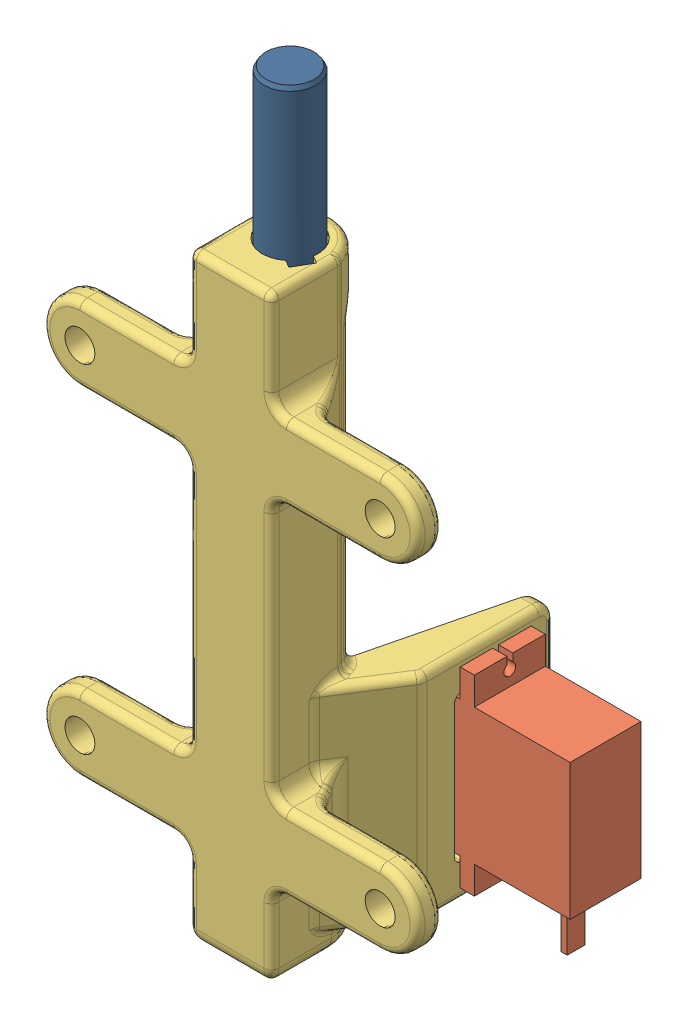
SolidWorks assembly PenHolder, configuration Default. Lengths in mm.
Overall size (64.55 127.8 48.11).
12 component instances, 11 part files, 16 mates.
Components (placement in the parent):
- Servo Lever-1: Servo Lever [Default] at (-0.5 -33.948 -30.734) x (0 -0.984808 -0.173648) z (0 -0.173648 0.984808) size (7.3 5 34)
- SG90 Servo-1: SG90 Servo [Default] at (9.8 -28.448 -30.734) x (0 1 0) z (0 0 1) size (37.7 30.3 12)
- PenHolder-1: PenHolder [Default] at origin size (63.5 101.91 40.64)
- Assembly Ink Cartridge Pilot G2-1: Assembly Ink Cartridge Pilot G2 [Default] at (-23.3837 87.5006 -54.1169) x (1 0 0) z (0 -1 0) size (8.33 8.33 120.93)
  - Ink Container Tube-2: Ink Container Tube [Default] at (23.3837 43.9569 29.8776) x (-1 0 0) z (0 1 0) size (6.2 88 6)
  - Ink Container Back Plug-1: Ink Container Back Plug [Default] at (23.3837 43.9569 29.8776) x (1 0 0) z (0 1 0) size (6 4.9 6)
  - Pen Tip Holder-1: Pen Tip Holder [Default] at (23.3837 43.9569 117.8776) x (0.558829 -0.829283 0) z (0.829283 0.558829 0) size (6 18.11 6)
  - Pen Tip-1: Pen Tip [Default] at (23.3837 43.9569 135.6644) x (0.943336 0.33184 0) z (-0.33184 0.943336 0) size (2.59 15.69 2.63)
  - Roller Ball-2: Roller Ball [Default] at (23.3837 43.9569 138.8644) x (0.307657 -0.299861 -0.903012) z (0.951494 0.099481 0.29114) size (0.5 0.5 0.5)
  - Spring-3: Spring [Write] at (23.3837 43.9569 20.2276) x (1 0 0) z (0 -1 0) size (7.26 11.16 7.26)
- Spring Cap-1: Spring Cap [Default] at (0 19.5395 -10.16) x (0.422618 0 0.906308) z (-0.906308 0 0.422618) size (8.89 56.52 10.92)
- Pen Lifter-1: Pen Lifter [Default] at (0 -42.799 -10.16) x (-1 0 0) z (0 0 -1) size (8.89 15.4 11.43)
Mates (geometry in assembly coordinates):
- Concentric1: concentric anti-aligned: cylinder of Servo Lever-1 through (4.5 -33.948 -30.734) axis (-1 0 0) radius 0.75; cylinder of SG90 Servo-1 through (5.5 -33.948 -30.734) axis (1 0 0) radius 6
- Coincident2: coordinate: point of PenHolder-1
- Concentric4: concentric anti-aligned: cylinder of PenHolder-1 through (0 -47.625 -10.16) axis (0 -1 0) radius 1.397; cylinder of Assembly Ink Cartridge Pilot G2-1/Ink Container Tube-2 through (0 -30.377 -10.16) axis (0 1 0) radius 3
- Coincident7: coincident anti-aligned: plane of Servo Lever-1 through (2.5 -33.948 -30.734) normal (1 0 0); plane of SG90 Servo-1 through (2.5 -28.448 -30.734) normal (-1 0 0)
- Parallel2: parallel aligned: plane of Assembly Ink Cartridge Pilot G2-1 through (-23.3837 87.5006 -54.1169) normal (0 0 1)
- Concentric5: concentric anti-aligned: cylinder of PenHolder-1 through (0 50.8 -10.16) axis (0 -1 0) radius 6.985; cylinder of Spring Cap-1 through (0 73.5145 -10.16) axis (0 1 0) radius 4.445
- Angle1: planar angle = 2.007129 rad anti-aligned: plane of Spring Cap-1 through (0 19.5395 -10.16) normal (-0.906308 0 0.422618)
- Concentric7: concentric anti-aligned: cylinder of PenHolder-1 through (0 50.8 -10.16) axis (0 -1 0) radius 4.699; cylinder of Pen Lifter-1 through (0 -31.877 -10.16) axis (0 1 0) radius 4.445
- Parallel5: parallel anti-aligned: plane of Pen Lifter-1 through (0 -42.799 -10.16) normal (0 0 -1)
- Symmetric2: symmetric aligned: plane of Servo Lever-1 through (-0.5 -31.3867 -45.2599) normal (-1 0 0); plane of Pen Lifter-1 through (0.5 -31.3867 -45.2599) normal (1 0 0); plane of Servo Lever-1 through (0 -42.799 -10.16) normal (-1 0 0)
- LimitAngle1: limit planar angle = 0.174533 rad aligned: plane of Servo Lever-1 through (-0.5 -33.948 -30.734) normal (0 -0.173648 0.984808); plane of SG90 Servo-1 through (9.8 -28.448 -30.734) normal (0 0 1)
- LimitDistance1: limit distance = 4.826 mm anti-aligned: plane of PenHolder-1 through (0 -47.625 -10.16) normal (0 1 0); plane of Pen Lifter-1 through (-4.445 -42.799 -10.16) normal (0 -1 0)
- Coincident14: coincident anti-aligned: plane of Assembly Ink Cartridge Pilot G2-1/Pen Tip Holder-1 through (0 -31.877 -10.16) normal (0 -1 0); plane of Pen Lifter-1 through (-2.3546 -31.877 -10.16) normal (0 1 0)
- Parallel6: parallel anti-aligned: plane of SG90 Servo-1 through (14.2 -28.448 -30.734) normal (-1 0 0); plane of PenHolder-1 through (14.2011 0 0) normal (1 0 0)
- Concentric8: concentric anti-aligned: cylinder of SG90 Servo-1 through (16.6 -14.4196 -30.734) axis (-1 0 0) radius 1; cylinder of PenHolder-1 through (11.6611 -14.4196 -30.734) axis (1 0 0) radius 0.635
- Parallel7: parallel aligned: plane of SG90 Servo-1 through (32.8 -39.948 -36.734) normal (0 0 -1); plane of PenHolder-1 through (11.6611 -12.248 -40.64) normal (0 0 -1)
